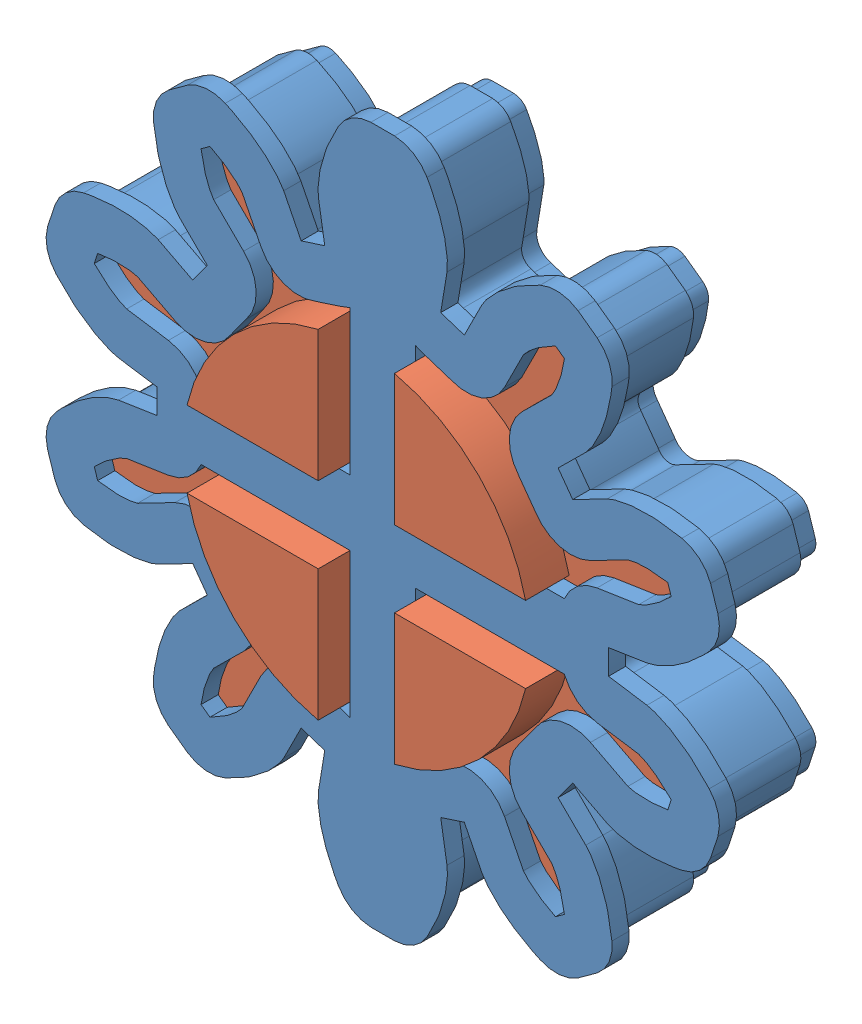
SolidWorks assembly gearcookiecutter, configuration without hole. Lengths in mm.
Overall size (78.47 81.29 17.09).
2 component instances, 2 part files, 6 mates.
Components (placement in the parent):
- geargoodcookie-1: geargoodcookie [without hole] at origin size (78.47 81.29 14.01)
- geargoodcookierelease-1: geargoodcookierelease [without hole] at (0 0 8.19) size (70.69 73.51 8.93)
Mates (geometry in assembly coordinates):
- Coincident1: coincident aligned: plane of geargoodcookie-1 through (0 0 0) normal (0 0 1)
- Coincident2: coincident aligned: plane of geargoodcookie-1 through (0 0 0) normal (0 1 0)
- Coincident3: coincident aligned: plane of geargoodcookie-1 through (0 0 0) normal (1 0 0)
- Coincident4: coincident anti-aligned: plane of geargoodcookie-1 through (33.9489 12.3192 12) normal (0 0 -1); plane of geargoodcookierelease-1 through (0 0 12) normal (0 0 1)
- Concentric1: concentric aligned: cylinder of geargoodcookie-1 through (0 0 158.242) axis (0 0 -1) radius 22.8562; cylinder of geargoodcookierelease-1 through (0 0 10.095) axis (0 0 -1) radius 22.4562
- Concentric2: concentric aligned: cylinder of geargoodcookie-1 through (-1.2255 36.0942 158.242) axis (0 0 -1) radius 1.0287; cylinder of geargoodcookierelease-1 through (-1.2255 36.0942 10.095) axis (0 0 -1) radius 0.6287
